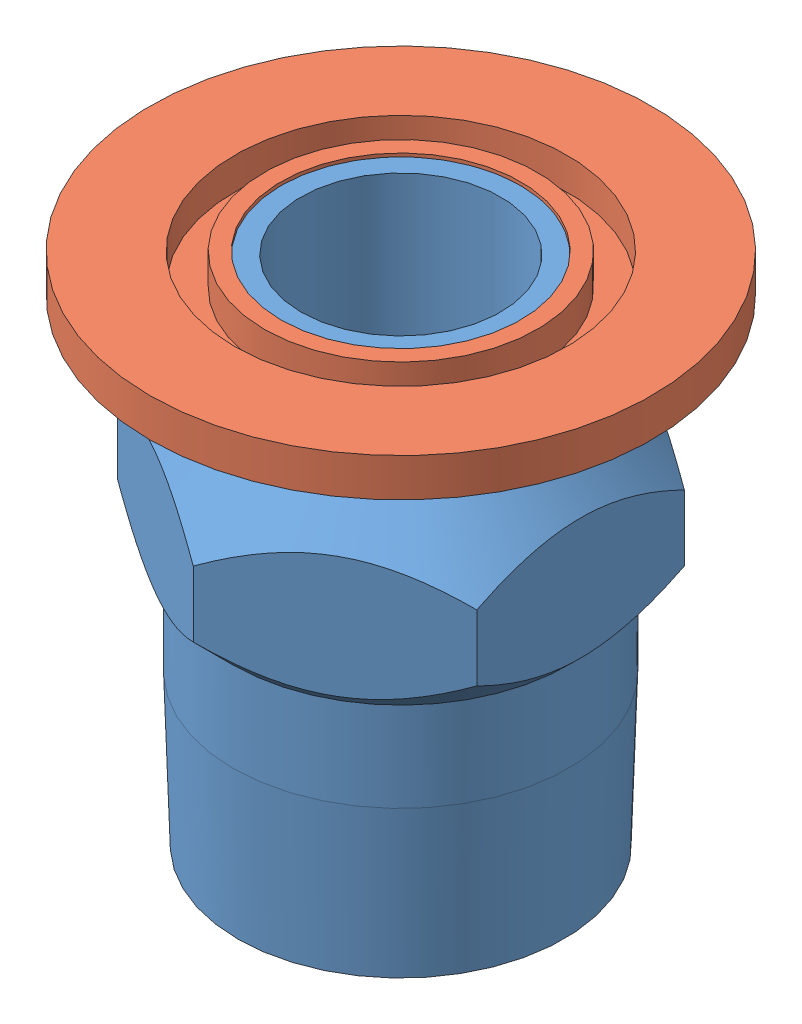
SolidWorks assembly 731025, configuration Default. Lengths in mm.
Overall size (39.93 40.89 39.93).
2 component instances, 2 part files, 2 mates.
Components (placement in the parent):
- 973103-1: 973103 [Default] at (18.4239 39.1799 31.0729) size (28.57 40.64 36.29)
- 973108-1: 973108 [Default] at (18.4239 39.4339 31.0729) x (0.999999 0 0.001242) z (-0.001242 0 0.999999) size (39.88 5.08 39.88)
Mates (geometry in assembly coordinates):
- Concentric1: concentric aligned: cylinder of 973103-1 through (18.4239 39.1799 31.0729) axis (0 1 0) radius 9.5123; cylinder of 973108-1 through (18.4239 39.4339 31.0729) axis (0 1 0) radius 9.525
- Coincident1: coincident anti-aligned: plane of 973103-1 through (27.9362 34.3539 31.0729) normal (0 1 0); plane of 973108-1 through (30.7793 34.3539 31.0883) normal (0 -1 0)
